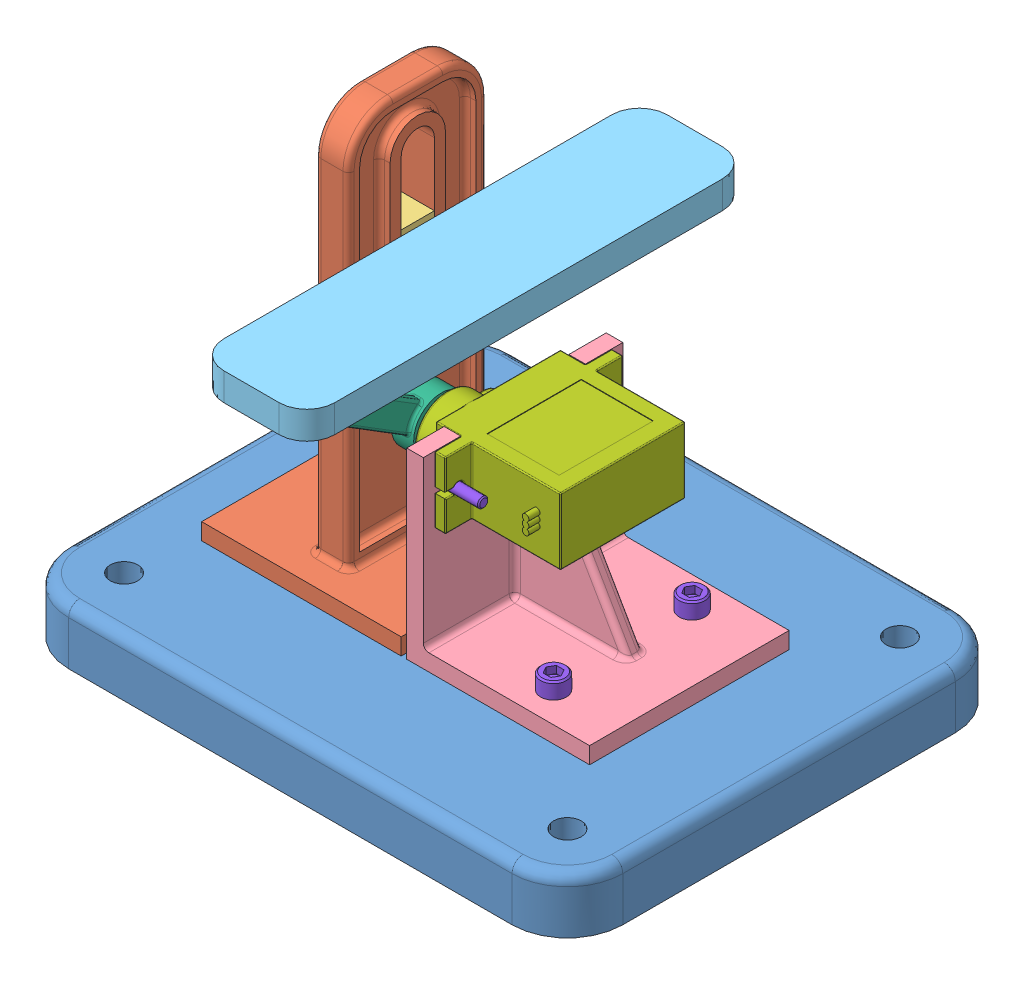
SolidWorks assembly motionStudy, configuration Default. Lengths in mm.
Overall size (100 83 80).
14 component instances, 8 part files, 33 mates.
Components (placement in the parent):
- base-1: base [Default] at (24.9242 19.8542 101.872) size (100 10 80)
- bracket-1: bracket [Default] at (4.9242 29.8542 101.872) size (36 73 36)
- clip-1: clip [Default] at (-0.0758 77.9408 101.872) x (0 0 1) z (0 1 0) size (10 8 7)
- servoMount-1: servoMount [Default] at (26.9242 32.8542 101.872) x (1 0 0) z (0 -1 0) size (33 36 33)
- shelf-1: shelf [Default] at (17.9242 80.4408 101.872) x (0 0 -1) z (-1 0 0) size (80 5 26)
- servoArm-1: servoArm [Default] at (15.4242 64.7696 119.8635) x (0 -0.527693 -0.849435) z (0 0.849435 -0.527693) size (38 4 10)
- Micro Servo FS90R Continuous-1: Micro Servo FS90R Continuous [Valor predeterminado] at (28.9242 56.8542 101.872) x (0 0 -1) z (0 1 0) size (32 29 12)
- socket head cap screw_ai-2: socket head cap screw_ai [HX-SHCS 0.112-40x0.375x0.375-N] at (44.9242 35.699 114.372) x (0 -1 0) z (0 0 1) size (12.37 4.65 4.65)
- socket head cap screw_ai-3: socket head cap screw_ai [HX-SHCS 0.112-40x0.375x0.375-N] at (14.9242 35.699 101.872) x (0 -1 0) z (0 0 1) size (12.37 4.65 4.65)
- socket head cap screw_ai-4: socket head cap screw_ai [HX-SHCS 0.112-40x0.375x0.375-N] at (-5.0758 35.699 101.872) x (0 -1 0) z (0 0 1) size (12.37 4.65 4.65)
- socket head cap screw_ai-5: socket head cap screw_ai [HX-SHCS 0.112-40x0.375x0.375-N] at (44.9242 35.699 89.372) x (0 -1 0) z (0 0 1) size (12.37 4.65 4.65)
- socket head cap screw_ai-10: socket head cap screw_ai [HX-SHCS 0.073-72x0.375x0.375-N] at (22.07 56.8542 115.497) x (1 0 0) z (0 -0.30454 0.9525) size (11.38 3 3)
- socket head cap screw_ai-11: socket head cap screw_ai [HX-SHCS 0.073-72x0.375x0.375-N] at (22.07 56.8542 88.247) x (1 0 0) z (0 -0.973375 0.22922) size (11.38 3 3)
- socket head cap screw_ai-12: socket head cap screw_ai [HX-SHCS 0.073-72x0.375x0.375-N] at (-1.93 77.9408 101.872) size (11.38 3 3)
Mates (geometry in assembly coordinates):
- Coincident1: coincident anti-aligned: plane of base-1 through (24.9242 29.8542 101.872) normal (0 1 0); plane of bracket-1 through (4.9242 29.8542 101.872) normal (0 -1 0)
- Concentric1: concentric aligned: cylinder of base-1 through (14.9242 19.8542 101.872) axis (0 1 0) radius 1.5; cylinder of bracket-1 through (14.9242 29.8542 101.872) axis (0 1 0) radius 1.5
- Concentric2: concentric aligned: cylinder of base-1 through (-5.0758 19.8542 101.872) axis (0 1 0) radius 1.5; cylinder of bracket-1 through (-5.0758 29.8542 101.872) axis (0 1 0) radius 1.5
- Coincident3: coincident anti-aligned: plane of base-1 through (24.9242 29.8542 101.872) normal (0 1 0); plane of servoMount-1 through (26.9242 29.8542 119.872) normal (0 -1 0)
- Concentric3: concentric aligned: cylinder of base-1 through (44.9242 19.8542 114.372) axis (0 1 0) radius 1.5; cylinder of servoMount-1 through (44.9242 29.8542 114.372) axis (0 1 0) radius 1.5
- Concentric4: concentric aligned: cylinder of base-1 through (44.9242 19.8542 89.372) axis (0 1 0) radius 1.5; cylinder of servoMount-1 through (44.9242 29.8542 89.372) axis (0 1 0) radius 1.5
- Coincident10: coincident anti-aligned: plane of clip-1 through (7.9242 75.4408 98.872) normal (0 1 0); plane of shelf-1 through (17.9242 75.4408 101.872) normal (0 -1 0)
- Coincident11: coincident anti-aligned: plane of clip-1 through (7.9242 80.4408 98.872) normal (0 -1 0); plane of shelf-1 through (17.9242 80.4408 101.872) normal (0 1 0)
- Coincident12: coincident anti-aligned: plane of clip-1 through (1.9242 77.9408 101.872) normal (1 0 0); plane of shelf-1 through (1.9242 80.4408 101.872) normal (-1 0 0)
- Coincident14: coincident anti-aligned: line of clip-1 through (7.9242 80.4408 98.872) axis (-1 0 0); line of shelf-1 through (1.9242 80.4408 98.872) axis (1 0 0)
- Coincident15: coincident anti-aligned: plane of bracket-1 through (-13.0758 92.8542 98.872) normal (0 0 1); plane of clip-1 through (7.9242 80.4408 98.872) normal (0 0 -1)
- Coincident16: coincident anti-aligned: plane of bracket-1 through (1.9242 102.8542 89.372) normal (-1 0 0); plane of clip-1 through (1.9242 77.9408 101.872) normal (1 0 0)
- Coincident23: coincident anti-aligned: plane of servoMount-1 through (23.9242 50.8542 113.122) normal (0 1 0); plane of Micro Servo FS90R Continuous-1 through (44.9242 50.8542 113.122) normal (0 -1 0)
- Coincident24: coincident anti-aligned: plane of servoMount-1 through (23.9242 62.8542 113.122) normal (0 0 -1); plane of Micro Servo FS90R Continuous-1 through (44.9242 50.8542 113.122) normal (0 0 1)
- Coincident25: coincident anti-aligned: plane of servoMount-1 through (23.9242 62.8542 90.622) normal (0 0 1); plane of Micro Servo FS90R Continuous-1 through (44.9242 50.8542 90.622) normal (0 0 -1)
- Concentric6: concentric anti-aligned: cylinder of servoArm-1 through (17.4242 56.8542 107.122) axis (-1 0 0) radius 2.25; cylinder of Micro Servo FS90R Continuous-1 through (15.9242 56.8542 107.122) axis (1 0 0) radius 2.25
- Distance1: distance = 1 mm anti-aligned: plane of servoArm-1 through (17.4242 56.8542 107.122) normal (1 0 0); plane of Micro Servo FS90R Continuous-1 through (18.4242 56.8542 107.122) normal (-1 0 0)
- Concentric7: concentric aligned: cylinder of servoMount-1 through (44.9242 29.8542 114.372) axis (0 1 0) radius 1.5; cylinder of socket head cap screw_ai-2 through (44.9242 67.449 114.372) axis (0 1 0) radius 2.3241
- Coincident29: coincident anti-aligned: plane of servoMount-1 through (26.9242 32.8542 119.872) normal (0 1 0); plane of socket head cap screw_ai-2 through (47.2483 32.8542 114.372) normal (0 -1 0)
- Concentric8: concentric aligned: cylinder of bracket-1 through (14.9242 29.8542 101.872) axis (0 1 0) radius 1.5; cylinder of socket head cap screw_ai-3 through (14.9242 67.449 101.872) axis (0 1 0) radius 2.3241
- Coincident30: coincident anti-aligned: plane of bracket-1 through (4.9242 32.8542 101.872) normal (0 1 0); plane of socket head cap screw_ai-3 through (17.2483 32.8542 101.872) normal (0 -1 0)
- Concentric9: concentric aligned: cylinder of bracket-1 through (-5.0758 29.8542 101.872) axis (0 1 0) radius 1.5; cylinder of socket head cap screw_ai-4 through (-5.0758 67.449 101.872) axis (0 1 0) radius 2.3241
- Coincident31: coincident anti-aligned: plane of bracket-1 through (4.9242 32.8542 101.872) normal (0 1 0); plane of socket head cap screw_ai-4 through (-2.7517 32.8542 101.872) normal (0 -1 0)
- Concentric10: concentric aligned: cylinder of servoMount-1 through (44.9242 29.8542 89.372) axis (0 1 0) radius 1.5; cylinder of socket head cap screw_ai-5 through (44.9242 67.449 89.372) axis (0 1 0) radius 2.3241
- Coincident32: coincident anti-aligned: plane of servoMount-1 through (26.9242 32.8542 119.872) normal (0 1 0); plane of socket head cap screw_ai-5 through (47.2483 32.8542 89.372) normal (0 -1 0)
- Concentric12: concentric anti-aligned: cylinder of clip-1 through (-0.0758 77.9408 101.872) axis (1 0 0) radius 1.425; cylinder of socket head cap screw_ai-12 through (-33.68 77.9408 101.872) axis (-1 0 0) radius 1.4986
- Coincident34: coincident anti-aligned: plane of clip-1 through (-0.0758 77.9408 101.872) normal (-1 0 0); plane of socket head cap screw_ai-12 through (-0.0758 79.4394 101.872) normal (1 0 0)
- Concentric13: concentric anti-aligned: cylinder of servoMount-1 through (23.9242 56.8542 115.497) axis (1 0 0) radius 1; cylinder of socket head cap screw_ai-10 through (-9.68 56.8542 115.497) axis (-1 0 0) radius 0.9271
- Concentric14: concentric anti-aligned: cylinder of servoMount-1 through (23.9242 56.8542 88.247) axis (1 0 0) radius 1; cylinder of socket head cap screw_ai-11 through (-9.68 56.8542 88.247) axis (-1 0 0) radius 0.9271
- Coincident37: coincident anti-aligned: plane of servoMount-1 through (26.9242 62.8542 119.872) normal (1 0 0); plane of Micro Servo FS90R Continuous-1 through (26.9242 56.8542 88.247) normal (-1 0 0)
- Coincident38: coincident anti-aligned: plane of servoMount-1 through (26.9242 62.8542 119.872) normal (1 0 0); plane of Micro Servo FS90R Continuous-1 through (26.9242 56.8542 115.497) normal (-1 0 0)
- Coincident39: coincident anti-aligned: plane of servoMount-1 through (23.9242 62.8542 119.872) normal (-1 0 0); plane of socket head cap screw_ai-11 through (23.9242 57.1977 89.7057) normal (1 0 0)
- Coincident40: coincident anti-aligned: plane of servoMount-1 through (23.9242 62.8542 119.872) normal (-1 0 0); plane of socket head cap screw_ai-10 through (23.9242 58.2816 115.9534) normal (1 0 0)
